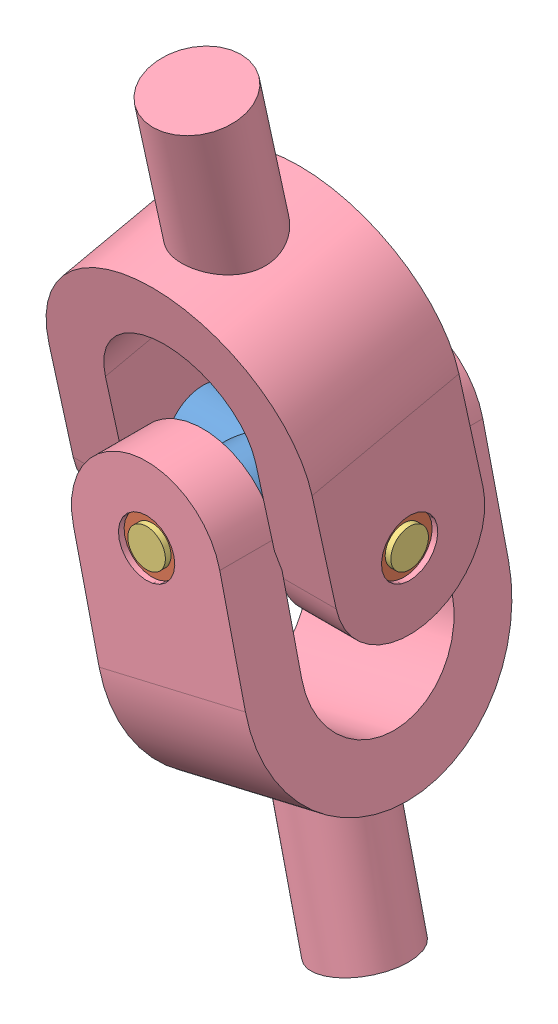
SolidWorks assembly Universal Joint 2003091, configuration Default. Lengths in mm.
Overall size (98.42 261.42 96.71).
11 component instances, 4 part files, 20 mates.
Components (placement in the parent):
- Swivel - 2003091-2: Swivel - 2003091 [Default] at origin size (54.61 25.4 54.61)
- Blushing 2003091-2: Blushing 2003091 [Default] at (0 0 -42.545) size (19.05 19.05 15.24)
- Blushing 2003091-3: Blushing 2003091 [Default] at (-42.545 0 0) x (0 0 -1) z (1 0 0) size (19.05 19.05 15.24)
- Blushing 2003091-4: Blushing 2003091 [Default] at (42.545 0 0) x (0 0 1) z (-1 0 0) size (19.05 19.05 15.24)
- Blushing 2003091-5: Blushing 2003091 [Default] at (0 0 42.545) x (-0.923728 -0.383049 0) z (0 0 -1) size (19.05 19.05 15.24)
- Pin 2003091-1: Pin 2003091 [Default] at (44.45 0 0) x (0 0 1) z (-1 0 0) size (12.7 12.7 34.29)
- Pin 2003091-2: Pin 2003091 [Default] at (0 0 44.45) x (-0.982483 0.186351 0) z (0 0 -1) size (12.7 12.7 34.29)
- Pin 2003091-3: Pin 2003091 [Default] at (0 0 -44.45) x (0.328176 -0.944616 0) z (0 0 1) size (12.7 12.7 34.29)
- Pin 2003091-4: Pin 2003091 [Default] at (-44.45 0 0) x (0 -0.31411 -0.949386) z (1 0 0) size (12.7 12.7 34.29)
- Yoke - 2003091-1: Yoke - 2003091 [Default] at (8.6847 -37.097 0) x (0 0 1) z (0.973674 0.227945 0) size (88.9 153.67 50.8)
- Yoke - 2003091-2: Yoke - 2003091 [Default] at (0 37.2172 8.1539) x (1 0 0) z (0 -0.214014 0.976831) size (88.9 153.67 50.8)
Mates (geometry in assembly coordinates):
- Coincident1: coincident anti-aligned: plane of Blushing 2003091-3 through (-27.305 0 0) normal (1 0 0); plane of Swivel - 2003091-2 through (-27.305 0 0) normal (-1 0 0)
- Coincident3: coincident anti-aligned: plane of Swivel - 2003091-2 through (0 0 27.305) normal (0 0 1); plane of Blushing 2003091-5 through (0 0 27.305) normal (0 0 -1)
- Coincident4: coincident anti-aligned: circle of Swivel - 2003091-2; circle of Blushing 2003091-5
- Coincident5: coincident anti-aligned: plane of Swivel - 2003091-2 through (27.305 0 0) normal (1 0 0); plane of Blushing 2003091-4 through (27.305 0 0) normal (-1 0 0)
- Coincident6: coincident anti-aligned: circle of Swivel - 2003091-2; circle of Blushing 2003091-4
- Coincident7: coincident anti-aligned: plane of Swivel - 2003091-2 through (0 0 -27.305) normal (0 0 -1); plane of Blushing 2003091-2 through (0 0 -27.305) normal (0 0 1)
- Coincident8: coincident aligned: circle of Swivel - 2003091-2; circle of Blushing 2003091-2
- Coincident9: coincident anti-aligned: cylinder of Blushing 2003091-4; cylinder of Pin 2003091-1 through (10.16 0 0) axis (1 0 0) radius 6.35
- Coincident10: coincident anti-aligned: circle of Blushing 2003091-5; cylinder of Pin 2003091-2 through (0 0 10.16) axis (0 0 1) radius 6.35
- Coincident11: coincident anti-aligned: circle of Blushing 2003091-2; cylinder of Pin 2003091-3 through (0 0 -10.16) axis (0 0 -1) radius 6.35
- Coincident13: coincident aligned: circle of Swivel - 2003091-2; circle of Blushing 2003091-3
- Coincident14: coincident anti-aligned: circle of Blushing 2003091-3; cylinder of Pin 2003091-4 through (-10.16 0 0) axis (-1 0 0) radius 6.35
- Concentric4: concentric anti-aligned: cylinder of Blushing 2003091-3 through (-27.305 0 0) axis (-1 0 0) radius 9.525; cylinder of Yoke - 2003091-2 through (44.45 0 0) axis (1 0 0) radius 9.525
- Concentric6: concentric: cylinder of Blushing 2003091-2 through (0 0 -27.305) axis (0 0 -1) radius 9.525; cylinder of Yoke - 2003091-1 through (0 0 44.45) axis (0 0 1) radius 9.525
- Width1: width: plane of Yoke - 2003091-1 through (33.416 -31.3072 -44.45) normal (0 0 -1); plane of Yoke - 2003091-1 through (33.416 -31.3072 44.45) normal (0 0 1); plane of Blushing 2003091-2 through (0 0 -42.545) normal (0 0 -1); plane of Blushing 2003091-5 through (0 0 42.545) normal (0 0 1)
- Width2: width: plane of Yoke - 2003091-2 through (44.45 31.7813 32.9654) normal (1 0 0); plane of Yoke - 2003091-2 through (-44.45 31.7813 32.9654) normal (-1 0 0); plane of Blushing 2003091-4 through (42.545 0 0) normal (1 0 0); plane of Blushing 2003091-3 through (-42.545 0 0) normal (-1 0 0)
- Coincident24: coincident aligned: plane of Pin 2003091-1 through (44.45 0 0) normal (1 0 0); plane of Yoke - 2003091-2 through (44.45 31.7813 32.9654) normal (1 0 0)
- Coincident25: coincident aligned: plane of Pin 2003091-3 through (0 0 -44.45) normal (0 0 -1); plane of Yoke - 2003091-1 through (33.416 -31.3072 -44.45) normal (0 0 -1)
- Coincident26: coincident aligned: plane of Pin 2003091-4 through (-44.45 0 0) normal (-1 0 0); plane of Yoke - 2003091-2 through (-44.45 31.7813 32.9654) normal (-1 0 0)
- Coincident27: coincident aligned: plane of Pin 2003091-2 through (0 0 44.45) normal (0 0 1); plane of Yoke - 2003091-1 through (33.416 -31.3072 44.45) normal (0 0 1)
